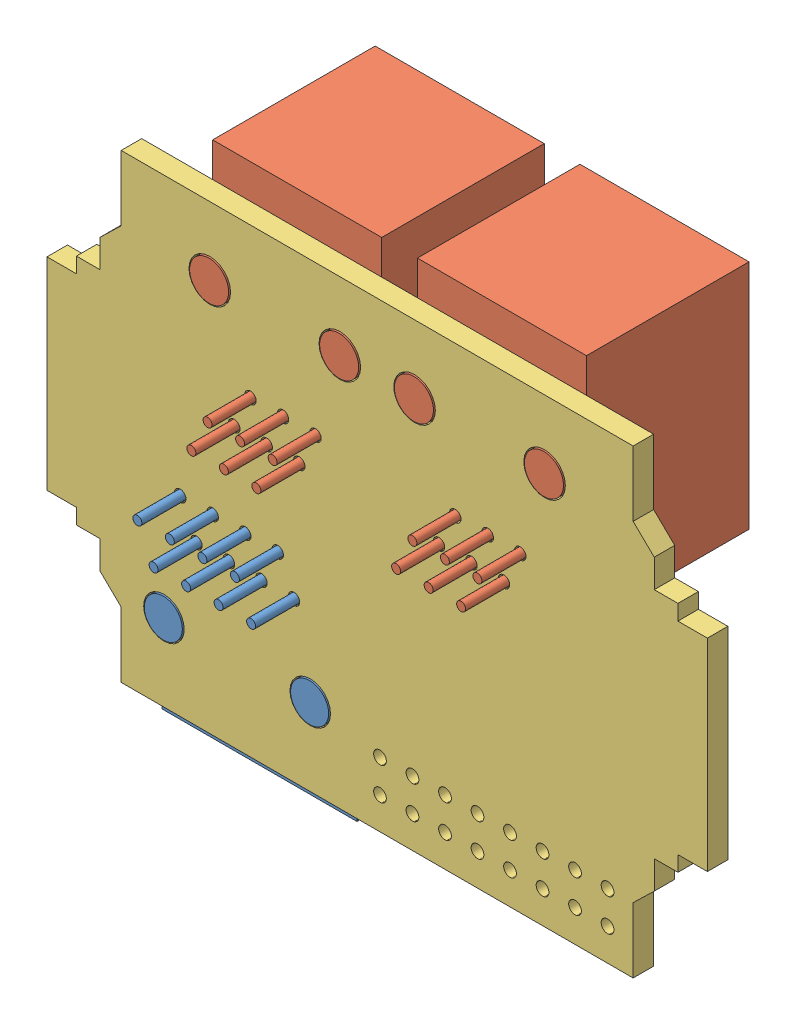
SolidWorks assembly IO-Base-PCB-Mouser, configuration Default. Lengths in mm.
Overall size (51.6 40.49 17.83).
8 component instances, 3 part files, 0 mates.
Components (placement in the parent):
- IO-Base-Mouser.STEP-1: IO-Base-Mouser.STEP [Default] at origin size (51.6 40.49 17.83)
  - SS-90000-001.STEP-1: SS-90000-001.STEP [Default] at (13.5 -18.5 -0.05) x (-1 0 0) z (0 0 -1) size (15.24 18.26 17.83)
    - COMPOUND.STEP-1: COMPOUND.STEP [Default] at origin size (15.24 18.26 17.83)
  - SS-90000-003.STEP-1: SS-90000-003.STEP [Default] at (8.83 -9.122 -0.05) x (1 0 0) z (0 0 -1) size (13.21 18.1 17.8)
    - COMPOUND-0.STEP-1: COMPOUND-0.STEP [Default] at origin size (13.21 18.1 17.8)
  - SS-90000-003.STEP-2: SS-90000-003.STEP [Default] at (24.83 -9.122 -0.05) x (1 0 0) z (0 0 -1) size (13.21 18.1 17.8)
    - COMPOUND-0.STEP-1: COMPOUND-0.STEP [Default] at origin size (13.21 18.1 17.8)
  - IO-Base-mouser PCB.STEP-1: IO-Base-mouser PCB.STEP [Default] at origin size (51.6 36 1.6)
